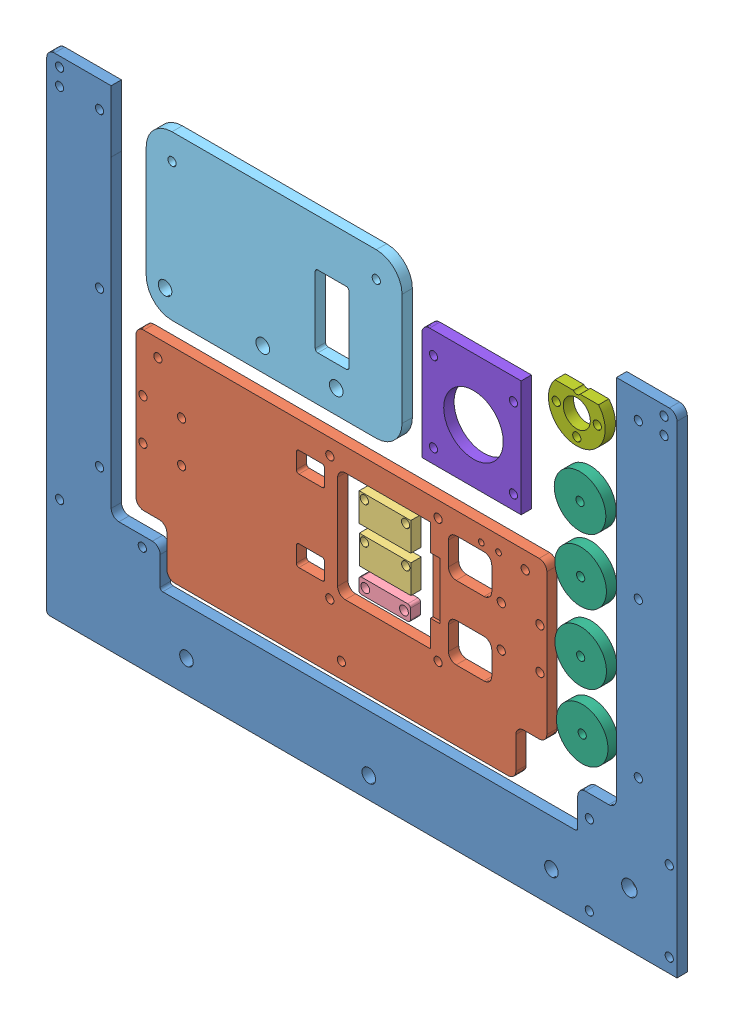
SolidWorks assembly Z AND Y FRAME PLUS SMALL ONES3 incomplete, configuration Default. Lengths in mm.
Overall size (255.5 200 4).
12 component instances, 8 part files, 19 mates.
Components (placement in the parent):
- Z Frame-2: Z Frame [Valor predeterminado] at (-101.1725 37.5207 0) size (250 190 4)
- Bed Support2-3: Bed Support2 [Default] at (31.4027 -73.1228 4) x (-1 0 0) z (0 0 -1) size (159.38 135.83 4)
- BELT HOLDER-3: BELT HOLDER [Default] at (-20.0811 -6.5358 4) x (-1 0 0) z (0 0 -1) size (20.01 11 4)
- BELT HOLDER-4: BELT HOLDER [Default] at (-20.0363 -20.7491 4) x (-1 0 0) z (0 0 -1) size (20.01 11 4)
- Hotend bracket-3: Hotend bracket [Valor predeterminado] at (-72.0957 -68.0472 137.3657) x (-1 0 0) z (0 0 -1) size (19.93 5.9 4)
- Small foot2-3: Small foot2 [Default] at (223.7937 -22.704 0) x (0 -1 0) z (0 0 1) size (63.38 99.24 4)
- foot-1: foot [Default] at (-72.662 -313.517 0) x (-1 0 0) z (0 0 1) size (20 20 4)
- foot-2: foot [Default] at (123.6711 265.2856 0) size (20 20 4)
- foot-3: foot [Default] at (123.6648 292.063 0) size (20 20 4)
- foot-4: foot [Default] at (123.4165 317.2045 0) size (20 20 4)
- Z nut atachment to X Bridge-1: Z nut atachment to X Bridge [Valor predeterminado] at (-79.9476 372.4659 0) size (22 18.05 4)
- motor spacer-1: motor spacer [Default] at (-60.4449 125.3732 0) size (38.5 45 4)
Mates (geometry in assembly coordinates):
- Coincident6: coincident anti-aligned: plane of Z Frame-2 through (-178.9289 86.4051 0) normal (0 0 -1); plane of assembly through (0 0 0) normal (0 0 1)
- Coincident7: coincident: plane of Z Frame-2 through (62.5711 -100.5949 4) normal (1 0 0); line of assembly
- Coincident8: coincident: plane of Z Frame-2 through (67.0711 -100.5949 4) normal (0 -1 0); line of assembly
- Coincident9: coincident aligned: plane of Z Frame-2 through (-178.9289 86.4051 4) normal (0 0 1); plane of Bed Support2-3 through (31.4027 -73.1228 4) normal (0 0 1)
- Coincident10: coincident aligned: plane of Bed Support2-3 through (31.4027 -73.1228 0) normal (0 0 -1); plane of BELT HOLDER-3 through (-20.0811 -6.5358 0) normal (0 0 -1)
- Coincident11: coincident aligned: plane of Z Frame-2 through (-178.9289 86.4051 4) normal (0 0 1); plane of Small foot2-3 through (223.7937 -22.704 4) normal (0 0 1)
- Parallel2: parallel anti-aligned: plane of Z Frame-2 through (-136.9289 -70.5949 4) normal (0 1 0); plane of Small foot2-3 through (-44.0757 22.3754 4) normal (0 -1 0)
- Coincident16: coincident aligned: plane of Z Frame-2 through (-178.9289 86.4051 4) normal (0 0 1); plane of foot-1 through (25.8016 -37.0118 4) normal (0 0 1)
- Coincident17: coincident aligned: plane of Z Frame-2 through (-178.9289 86.4051 4) normal (0 0 1); plane of motor spacer-1 through (-33.3739 66.7783 4) normal (0 0 1)
- Coincident19: coincident aligned: plane of Bed Support2-3 through (31.4027 -73.1228 0) normal (0 0 -1); plane of Hotend bracket-3 through (-72.0957 -68.0472 0) normal (0 0 -1)
- Coincident20: coincident aligned: plane of Bed Support2-3 through (31.4027 -73.1228 0) normal (0 0 -1); plane of BELT HOLDER-4 through (-20.0363 -20.7491 0) normal (0 0 -1)
- Coincident21: coincident aligned: plane of Z Frame-2 through (-178.9289 86.4051 0) normal (0 0 -1); plane of foot-2 through (25.2075 -11.2195 0) normal (0 0 -1)
- Coincident22: coincident aligned: plane of Z Frame-2 through (-178.9289 86.4051 0) normal (0 0 -1); plane of foot-3 through (25.2012 15.5578 0) normal (0 0 -1)
- Coincident23: coincident aligned: plane of Z Frame-2 through (-178.9289 86.4051 0) normal (0 0 -1); plane of foot-4 through (24.9529 40.6994 0) normal (0 0 -1)
- Coincident25: coincident aligned: plane of Z Frame-2 through (-178.9289 86.4051 0) normal (0 0 -1); plane of Z nut atachment to X Bridge-1 through (23.699 69.7 0) normal (0 0 -1)
- Parallel3: parallel: line of Z Frame-2 through (-136.9289 -70.5949 4) axis (1 0 0); plane of Bed Support2-3 through (0.0919 -65.3857 0) normal (0 -1 0)
- Parallel4: parallel: line of Bed Support2-3 through (-66.0986 -37.8425 4) axis (1 0 0); plane of Hotend bracket-3 through (-40.8736 -33.0074 0) normal (0 -1 0)
- Parallel5: parallel anti-aligned: line of Bed Support2-3 through (-66.0986 -37.8425 4) axis (1 0 0); line of BELT HOLDER-4 through (-40.6549 -23.7491 4) axis (-1 0 0)
- Parallel6: parallel anti-aligned: line of Bed Support2-3 through (-66.0986 -37.8425 4) axis (1 0 0); line of BELT HOLDER-3 through (-40.6996 -9.5358 4) axis (-1 0 0)
